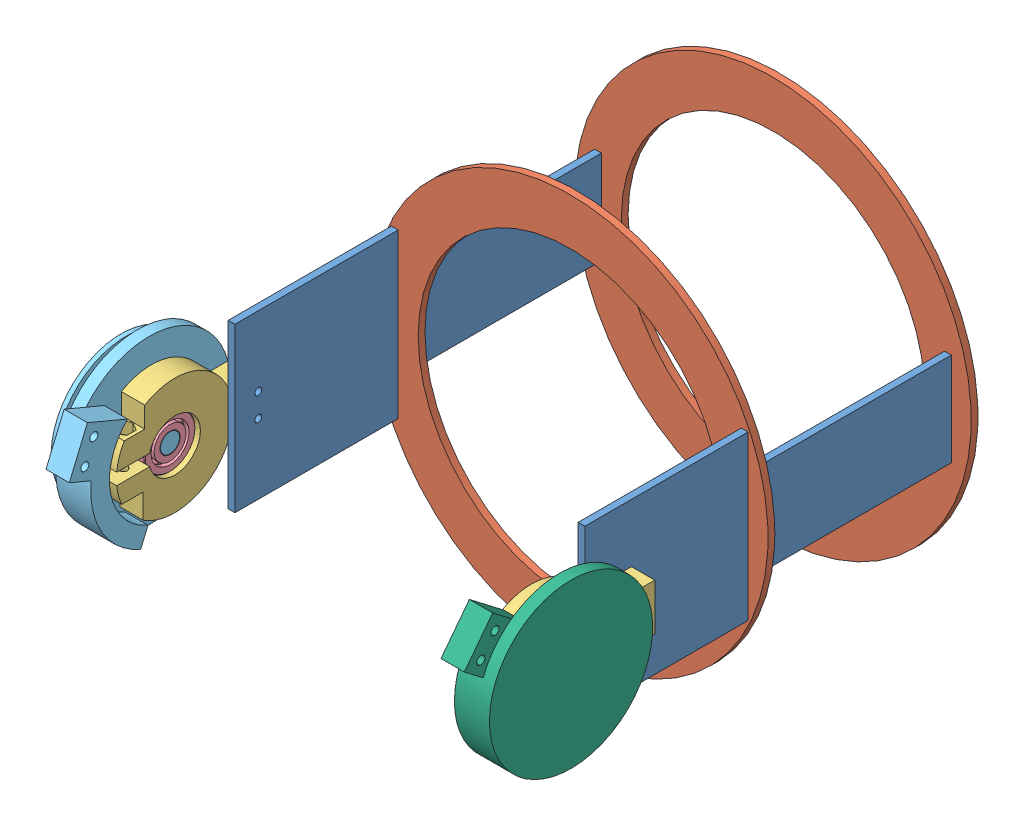
SolidWorks assembly upper&joint, configuration Default. Lengths in mm.
Overall size (192.9 170 238.92).
12 component instances, 6 part files, 15 mates.
Components (placement in the parent):
- arm_side-1: arm_side [Default] at (61.6277 91.8956 160.3378) size (2.9 70 160)
- arm_ring-1: arm_ring [Default] at (-11.9223 91.8956 122.4378) size (170 170 2.9)
- arm_side-2: arm_side [Default] at (-88.3723 91.8956 160.3378) size (2.9 70 160)
- arm_ring-2: arm_ring [Default] at (-11.9223 91.8956 35.3378) size (170 170 2.9)
- elbow_joint-2: elbow_joint [Default] at (-146.2367 131.4384 190.8682) x (0 0 1) z (1 0 0) size (99.72 95.06 23)
  - joint_upper_22mmID-1: joint_upper_22mmID [Default] at (27.3835 39.5429 47.8644) size (67.79 50 10)
  - 22mm_BALL BEARING-1: 22mm_BALL BEARING [5972K91] at (27.3835 39.5429 52.3644) size (22 22 7)
  - joint_lower_8mmOD-1: joint_lower_8mmOD [Default] at (27.3835 39.5429 55.8644) x (-0.387907 -0.921699 0) z (0 0 -1) size (70 78.74 22)
- elbow_joint_noDisk-2: elbow_joint_noDisk [Default] at (14.9997 130.1588 192.3733) x (0 0 1) z (1 0 0) size (105.08 103.48 17)
  - joint_upper_22mmID-1: joint_upper_22mmID [Default] at (25.8784 38.2633 49.528) size (67.79 50 10)
  - 22mm_BALL BEARING-1: 22mm_BALL BEARING [5972K91] at (25.8784 38.2633 56.028) size (22 22 7)
  - joint_lower_8mmOD_flat-1: joint_lower_8mmOD_flat [Default] at (25.8784 38.2633 52.528) x (0.609402 0.792861 0) z (0 0 1) size (70 78.74 15)
Mates (geometry in assembly coordinates):
- Coincident3: coincident anti-aligned: plane of arm_side-1 through (64.5277 71.8956 125.3378) normal (0 0 -1); plane of arm_ring-1 through (-11.9223 91.8956 125.3378) normal (0 0 1)
- Coincident4: coincident anti-aligned: plane of arm_side-1 through (64.5277 71.8956 35.3378) normal (0 -1 0); plane of arm_ring-1 through (64.5277 71.8956 125.3378) normal (0 1 0)
- Coincident5: coincident anti-aligned: plane of arm_side-1 through (61.6277 91.8956 160.3378) normal (-1 0 0); plane of arm_ring-1 through (61.6277 111.8956 125.3378) normal (1 0 0)
- Coincident6: coincident anti-aligned: plane of arm_ring-1 through (-11.9223 91.8956 125.3378) normal (0 0 1); plane of arm_side-2 through (-85.4723 71.8956 125.3378) normal (0 0 -1)
- Coincident7: coincident anti-aligned: plane of arm_ring-1 through (-85.4723 111.8956 125.3378) normal (-1 0 0); plane of arm_side-2 through (-85.4723 91.8956 160.3378) normal (1 0 0)
- Coincident8: coincident anti-aligned: plane of arm_ring-1 through (-88.3723 111.8956 125.3378) normal (0 -1 0); plane of arm_side-2 through (-85.4723 111.8956 35.3378) normal (0 1 0)
- Coincident10: coincident anti-aligned: plane of arm_side-2 through (-85.4723 91.8956 160.3378) normal (1 0 0); plane of arm_ring-2 through (-85.4723 111.8956 38.2378) normal (-1 0 0)
- Coincident11: coincident anti-aligned: plane of arm_side-2 through (-85.4723 111.8956 35.3378) normal (0 1 0); plane of arm_ring-2 through (-88.3723 111.8956 38.2378) normal (0 -1 0)
- Coincident12: coincident aligned: plane of arm_side-2 through (-85.4723 71.8956 35.3378) normal (0 0 -1); plane of arm_ring-2 through (-11.9223 91.8956 35.3378) normal (0 0 -1)
- Coincident17: coincident anti-aligned: plane of arm_side-2 through (-88.3723 91.8956 160.3378) normal (-1 0 0); plane of elbow_joint-2/joint_upper_22mmID-1 through (-88.3723 91.8956 218.2517) normal (1 0 0)
- Concentric4: concentric aligned: cylinder of arm_side-2 through (-85.4723 86.8956 185.3378) axis (-1 0 0) radius 1.5; cylinder of elbow_joint-2/joint_upper_22mmID-1 through (-88.3723 86.8956 185.3378) axis (-1 0 0) radius 1.75
- Concentric5: concentric aligned: cylinder of arm_side-2 through (-85.4723 96.8956 185.3378) axis (-1 0 0) radius 1.5; cylinder of elbow_joint-2/joint_upper_22mmID-1 through (-88.3723 96.8956 185.3378) axis (-1 0 0) radius 1.75
- Concentric8: concentric: cylinder of arm_side-1 through (64.5277 96.8956 185.3378) axis (-1 0 0) radius 1.5; cylinder of elbow_joint_noDisk-2/joint_upper_22mmID-1 through (74.5277 96.8956 185.3378) axis (-1 0 0) radius 1.75
- Concentric9: concentric: cylinder of arm_side-1 through (64.5277 86.8956 185.3378) axis (-1 0 0) radius 1.5; circle of elbow_joint_noDisk-2/joint_upper_22mmID-1
- Coincident18: coincident anti-aligned: plane of arm_side-1 through (64.5277 91.8956 160.3378) normal (1 0 0); plane of elbow_joint_noDisk-2/joint_upper_22mmID-1 through (64.5277 91.8956 218.2517) normal (-1 0 0)
